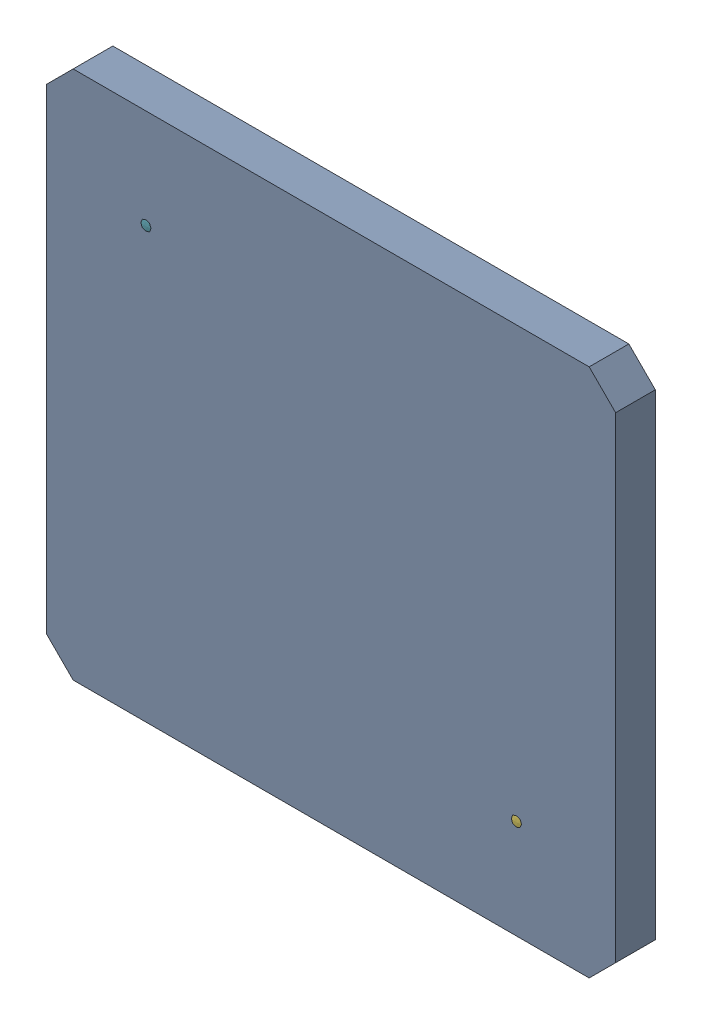
SolidWorks assembly Open CASCADE STEP translator 6.8 1.34.1, configuration Défaut. Lengths in mm.
Overall size (43 40 9.6).
7 component instances, 7 part files, 0 mates.
Components (placement in the parent):
- Body_1_16-1: Body_1_16 [Défaut] at origin size (43 40 3)
- Pin_1_12-1: Pin_1_12 [Défaut] at (7.754 -9.626 0) x (0 -1 0) z (0 0 1) size (0.66 0.66 7.16)
- Pin_2_12-1: Pin_2_12 [Défaut] at (10.294 -12.166 0) x (0 -1 0) z (0 0 1) size (0.66 0.66 7.16)
- Pin_3_8-1: Pin_3_8 [Défaut] at (12.834 -14.706 0) x (0 -1 0) z (0 0 1) size (0.66 0.66 7.16)
- Pin_4_6-1: Pin_4_6 [Défaut] at (15.374 -17.246 0) x (0 -1 0) z (0 0 1) size (0.66 0.66 7.16)
- Pin_5_5-1: Pin_5_5 [Défaut] at (53 3 0) x (0 -1 0) z (0 0 1) size (3.1 3.1 9.6)
- Pin_6_5-1: Pin_6_5 [Défaut] x (0 -1 0) z (0 0 1) size (3.1 3.1 9.6)
